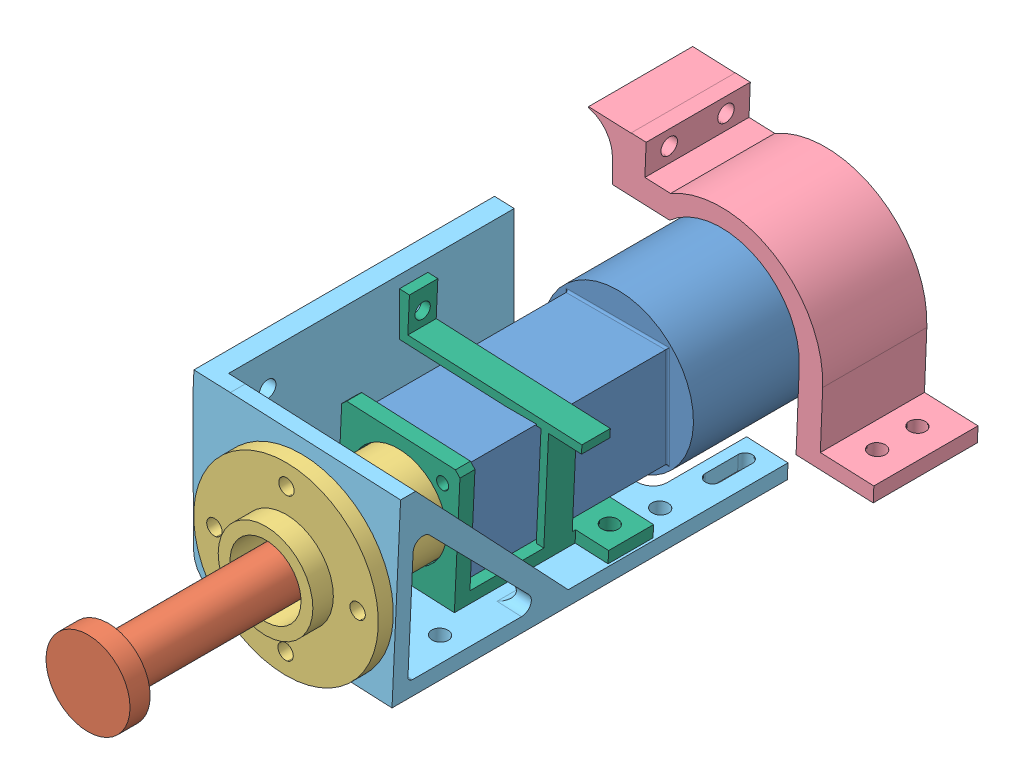
SolidWorks assembly assemblage moteur_simplifie-braquette-sol_sansPlancher_Miroir, configuration Default. Lengths in mm.
Overall size (180.67 88.54 311.5).
7 component instances, 6 part files, 7 mates.
Components (placement in the parent):
- assemblage_moteur_pla_simplifie-1: assemblage_moteur_pla_simplifie [Default] at (-32.6554 239.0613 952.694) x (0 0 1) z (0 1 0) size (311.5 78.45 78.45)
  - moteur_pla_simplifie-2: moteur_pla_simplifie [Default] at (-156.9384 51.1827 137.4238) size (176.5 64 64)
  - moteur_axe_pla_simplifie-1: moteur_axe_pla_simplifie [Default] at (3.5616 51.1827 137.4238) size (151 35.5 35.5)
  - front_housing_moteur_pla_simplifie-2: front_housing_moteur_pla_simplifie [Default] at (64.5616 51.1827 137.4238) x (1 0 0) z (0 0.00581 0.999983) size (60 78 78)
- braquette moteur- v2-1: braquette moteur- v2 [Default] at (18.5239 376.4853 839.7557) x (0.99917 -0.04074 0) z (0 0 1) size (123.62 80 44)
- braquette bleue_mirroir-1: braquette bleue_mirroir [Default] at (56.9516 341.6631 1017.2557) x (0 0 -1) z (0.998921 -0.046441 0) size (167 78 87.38)
- braquette gearbox_miroir_sansRef-1: braquette gearbox_miroir_sansRef [Default] at (70.4037 352.3999 976.2757) x (0 0 -1) z (-0.046441 -0.998921 0) size (72.34 158.52 66.5)
Mates (geometry in assembly coordinates):
- Concentric24: concentric anti-aligned: cylinder of assemblage_moteur_pla_simplifie-1/moteur_pla_simplifie-2 through (18.5273 376.4851 883.4757) axis (0 0 -1) radius 32; cylinder of braquette moteur- v2-1 through (18.5273 376.4851 795.7557) axis (0 0 1) radius 33
- Concentric25: concentric anti-aligned: cylinder of assemblage_moteur_pla_simplifie-1/front_housing_moteur_pla_simplifie-2 through (18.5273 376.4851 972.2557) axis (0 0 1) radius 20; cylinder of braquette bleue_mirroir-1 through (18.5273 376.4851 1017.2567) axis (0 0 -1) radius 20.25
- Coincident1: coincident anti-aligned: plane of assemblage_moteur_pla_simplifie-1/front_housing_moteur_pla_simplifie-2 through (18.5273 376.4851 1017.2557) normal (0 0 -1); plane of braquette bleue_mirroir-1 through (136.8652 337.9478 1017.2557) normal (0 0 1)
- Coincident2: coincident aligned: plane of assemblage_moteur_pla_simplifie-1/moteur_pla_simplifie-2 through (18.5273 376.4851 795.7557) normal (0 0 -1); plane of braquette moteur- v2-1 through (18.5577 374.1123 795.7557) normal (0 0 -1)
- Concentric27: concentric aligned: cylinder of braquette bleue_mirroir-1 through (46.9623 342.1265 915.7757) axis (0.046441 0.998921 0) radius 3.5; cylinder of braquette gearbox_miroir_sansRef-1 through (47.2572 348.4697 915.7757) axis (0.046441 0.998921 0) radius 3.5
- Coincident5: coincident anti-aligned: plane of braquette bleue_mirroir-1 through (137.1601 344.291 850.2557) normal (0.046441 0.998921 0); plane of braquette gearbox_miroir_sansRef-1 through (70.1715 347.4053 976.2757) normal (-0.046441 -0.998921 0)
- Parallel3: parallel aligned: plane of braquette moteur- v2-1 through (-26.9023 425.2812 766.5228) normal (0.04074 0.99917 0); plane of braquette bleue_mirroir-1 through (-26.72 423.5494 931.403) normal (0.04074 0.99917 0)
